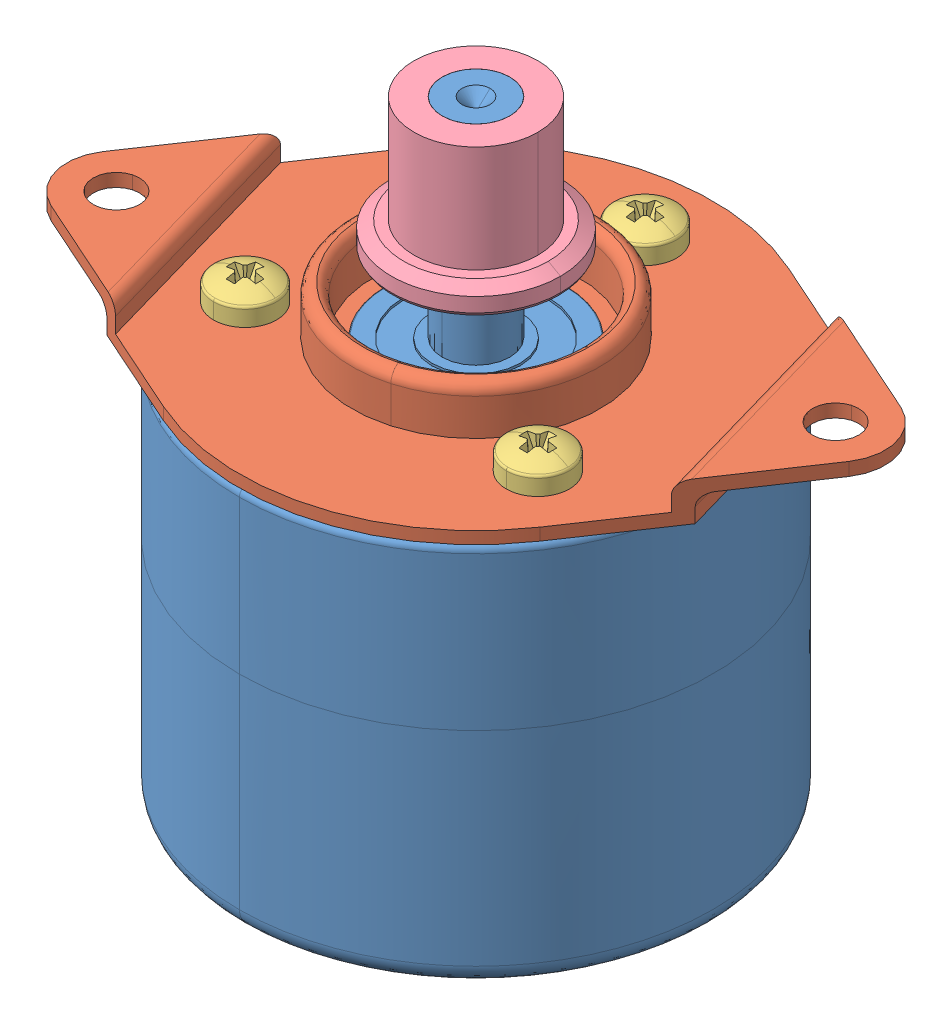
SolidWorks assembly Motor, configuration Default. Lengths in mm.
Overall size (69.62 53.75 56.99).
6 component instances, 4 part files, 0 mates.
Components (placement in the parent):
- motor.STEP-1: motor.STEP [Default] at origin size (48.19 53.75 42)
- mount_plate.STEP-1: mount_plate.STEP [Default] at (0 14.3 0) x (0.961464 0 -0.274932) z (0.274932 0 0.961464) size (60.4 5.33 42)
- pan head cross recess screw_iso_ISO 7045 - M3 x 4 - Z - 4N.STEP-1: pan head cross recess screw_iso_ISO 7045 - M3 x 4 - Z - 4N.STEP [Default] at (0 17.78 -15) x (0 -1 0) z (0 0 1) size (6.36 5.6 5.6)
- pan head cross recess screw_iso_ISO 7045 - M3 x 4 - Z - 4N.STEP-2: pan head cross recess screw_iso_ISO 7045 - M3 x 4 - Z - 4N.STEP [Default] at (-12.9904 17.78 7.5) x (0 -1 0) z (0 0 1) size (6.36 5.6 5.6)
- pan head cross recess screw_iso_ISO 7045 - M3 x 4 - Z - 4N.STEP-3: pan head cross recess screw_iso_ISO 7045 - M3 x 4 - Z - 4N.STEP [Default] at (12.9904 17.78 7.5) x (0 -1 0) z (0 0 1) size (6.36 5.6 5.6)
- pulley_nidec.STEP-1: pulley_nidec.STEP [Default] at (0 33.9 0) x (1 0 0) z (0 1 0) size (15 15 11.6)
